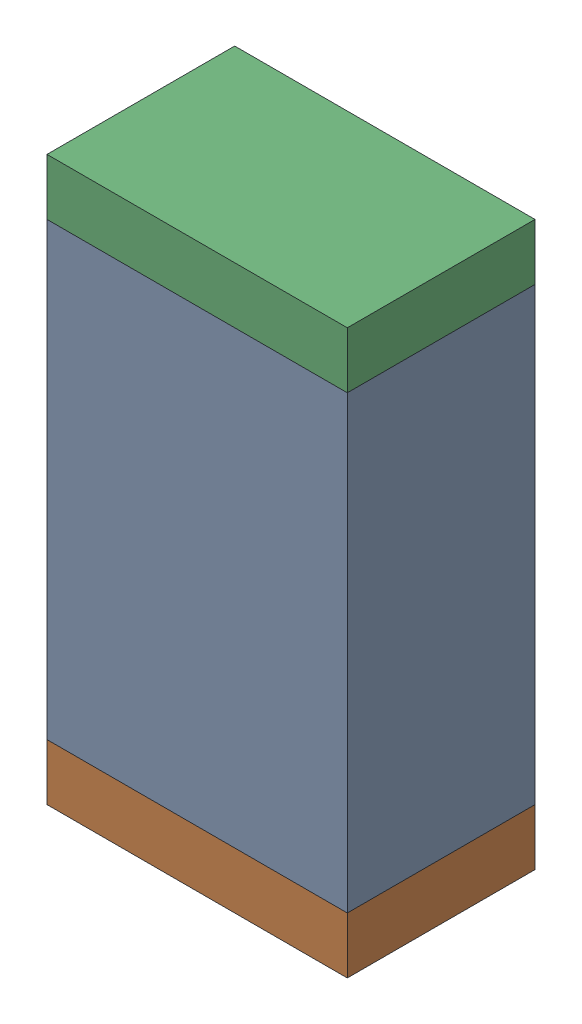
SolidWorks assembly R17, configuration Default. Lengths in mm.
Overall size (0.8 1.5 0.5).
6 component instances, 2 part files, 0 mates.
Components (placement in the parent):
- 810156976-1: 810156976 [Default] at (125.6 40.8 0) size (0.8 1.2 0.5)
  - Extruded_6-1: Extruded_6 [Default] at origin size (0.8 1.2 0.5)
- 810156592-1: 810156592 [Default] at (125.6 40.125 0) size (0.8 0.15 0.5)
  - Extruded_7-1: Extruded_7 [Default] at origin size (0.8 0.15 0.5)
- 810156592-2: 810156592 [Default] at (125.6 41.475 0) size (0.8 0.15 0.5)
  - Extruded_7-1: Extruded_7 [Default] at origin size (0.8 0.15 0.5)
